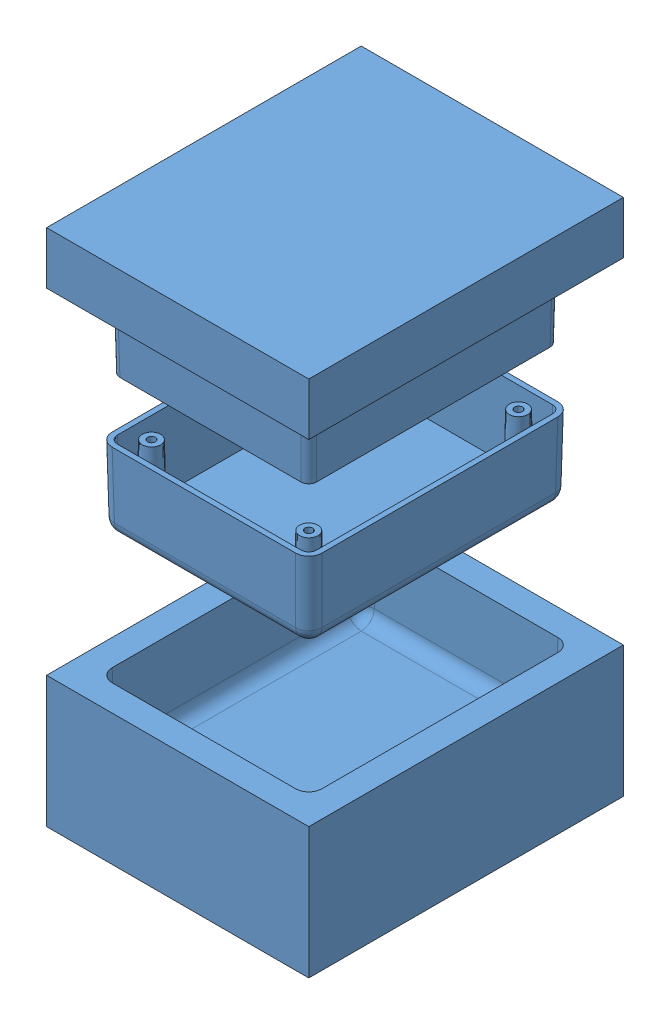
SolidWorks assembly EDR_box1, configuration Default. Lengths in mm.
Overall size (100 197.85 120).
2 component instances, 2 part files, 0 mates.
Components (placement in the parent):
- bottom_part1-1: bottom_part1 [Default] at (24.9648 55.7616 80.8525) size (100 197.85 120)
- top_part1-1: top_part1 [Default] at origin (suppressed, hidden)
